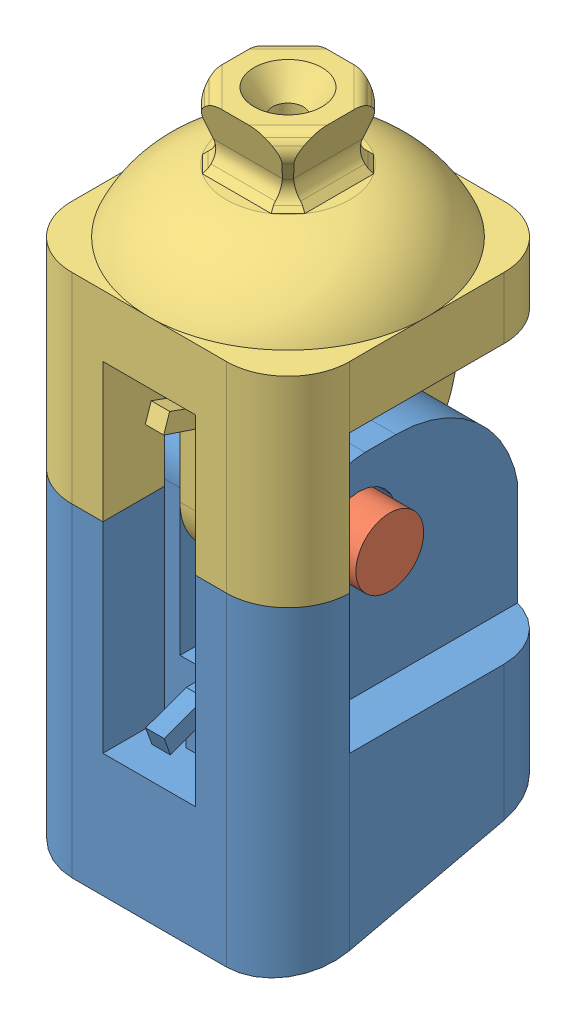
SolidWorks assembly Linear Spring Assembly, configuration Default. Lengths in mm.
Overall size (45 106 45).
3 component instances, 3 part files, 5 mates.
Components (placement in the parent):
- Linear Spring Bottom Half-1: Linear Spring Bottom Half [Default] at (16.1877 17.7469 58.728) size (45 63.5 45)
- Linear Spring Pin-1: Linear Spring Pin [Default] at (58.6877 70.2469 39.728) x (1 0 0) z (0 0.128788 0.991672) size (40 15 15)
- Linear Spring Top Half-2: Linear Spring Top Half [Default] at (38.6877 118.2469 36.228) size (45 64.5 45)
Mates (geometry in assembly coordinates):
- Coincident4: coincident anti-aligned: plane of Linear Spring Bottom Half-1 through (43.6877 81.2469 13.728) normal (-1 0 0); plane of Linear Spring Top Half-2 through (43.6877 59.2469 48.728) normal (1 0 0)
- Coincident5: coincident aligned: plane of Linear Spring Bottom Half-1 through (16.1877 47.7469 58.728) normal (0 0 1); plane of Linear Spring Top Half-2 through (16.1877 92.7469 58.728) normal (0 0 1)
- Coincident6: coincident anti-aligned: plane of Linear Spring Bottom Half-1 through (16.1877 70.2469 58.728) normal (0 1 0); plane of Linear Spring Top Half-2 through (38.6877 70.2469 36.228) normal (0 -1 0)
- Concentric1: concentric aligned: cylinder of Linear Spring Bottom Half-1 through (16.1877 70.2469 39.728) axis (1 0 0) radius 6; cylinder of Linear Spring Pin-1 through (23.6877 70.2469 39.728) axis (1 0 0) radius 5.5
- Coincident7: coincident anti-aligned: plane of Linear Spring Bottom Half-1 through (23.6877 81.2469 13.728) normal (-1 0 0); plane of Linear Spring Pin-1 through (23.6877 70.2469 39.728) normal (1 0 0)
